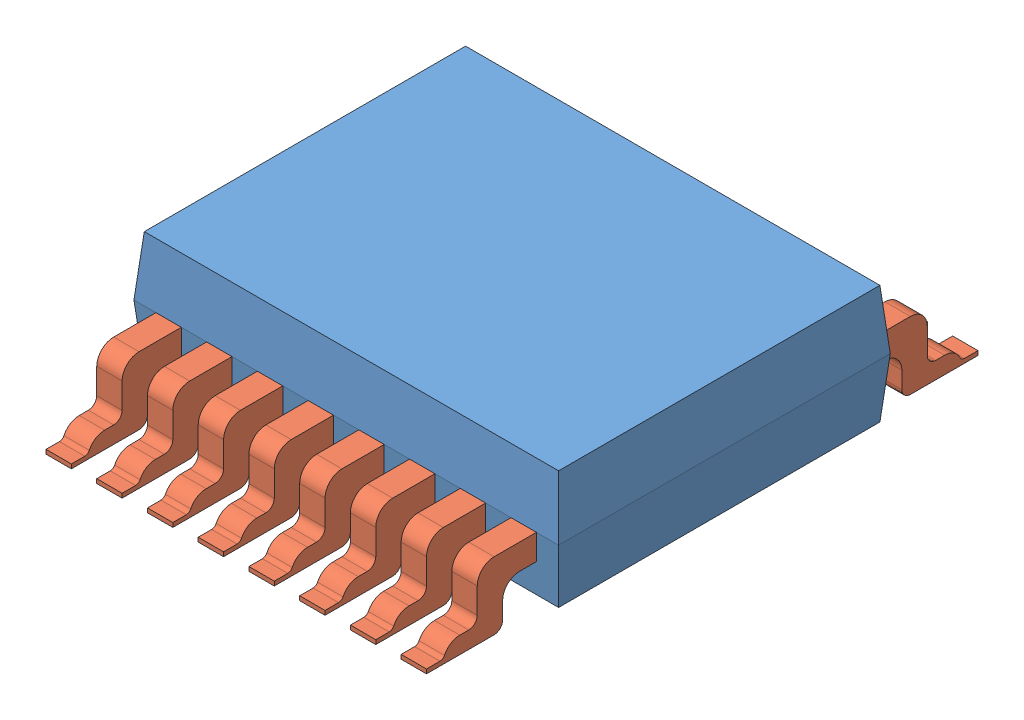
SolidWorks assembly P9813-SSOP16, configuration Défaut. Lengths in mm.
Overall size (5.02 1.5 6.52).
17 component instances, 2 part files, 2 mates.
Components (placement in the parent):
- P9813 Box-1: P9813 Box [Défaut] at (-2.298 -0.5448 6.9225) size (5.02 1.4 3.92)
- P9813 Foot-1: P9813 Foot [Défaut] at (2.1008 -0.6448 2.6612) size (0.3 0.8 1.3)
- P9813 Foot-17: P9813 Foot [Défaut] at (1.5008 -0.6448 2.6612) size (0.3 0.8 1.3)
- P9813 Foot-18: P9813 Foot [Défaut] at (0.9008 -0.6448 2.6612) size (0.3 0.8 1.3)
- P9813 Foot-19: P9813 Foot [Défaut] at (0.3008 -0.6448 2.6612) size (0.3 0.8 1.3)
- P9813 Foot-20: P9813 Foot [Défaut] at (-0.2992 -0.6448 2.6612) size (0.3 0.8 1.3)
- P9813 Foot-21: P9813 Foot [Défaut] at (-0.8992 -0.6448 2.6612) size (0.3 0.8 1.3)
- P9813 Foot-22: P9813 Foot [Défaut] at (-1.4992 -0.6448 2.6612) size (0.3 0.8 1.3)
- P9813 Foot-23: P9813 Foot [Défaut] at (-2.0992 -0.6448 2.6612) size (0.3 0.8 1.3)
- P9813 Foot-25: P9813 Foot [Défaut] at (2.4008 -0.6448 7.3837) x (-1 0 0) z (0 0 -1) size (0.3 0.8 1.3)
- P9813 Foot-26: P9813 Foot [Défaut] at (1.8008 -0.6448 7.3837) x (-1 0 0) z (0 0 -1) size (0.3 0.8 1.3)
- P9813 Foot-27: P9813 Foot [Défaut] at (1.2008 -0.6448 7.3837) x (-1 0 0) z (0 0 -1) size (0.3 0.8 1.3)
- P9813 Foot-28: P9813 Foot [Défaut] at (0.6008 -0.6448 7.3837) x (-1 0 0) z (0 0 -1) size (0.3 0.8 1.3)
- P9813 Foot-29: P9813 Foot [Défaut] at (0.0008 -0.6448 7.3837) x (-1 0 0) z (0 0 -1) size (0.3 0.8 1.3)
- P9813 Foot-30: P9813 Foot [Défaut] at (-0.5992 -0.6448 7.3837) x (-1 0 0) z (0 0 -1) size (0.3 0.8 1.3)
- P9813 Foot-31: P9813 Foot [Défaut] at (-1.1992 -0.6448 7.3837) x (-1 0 0) z (0 0 -1) size (0.3 0.8 1.3)
- P9813 Foot-32: P9813 Foot [Défaut] at (-1.7992 -0.6448 7.3837) x (-1 0 0) z (0 0 -1) size (0.3 0.8 1.3)
Mates (geometry in assembly coordinates):
- Parallèle10: parallel aligned: plane of box-1 through (-2.298 -0.5448 6.9225) normal (0 -1 0); plane of foot-1 through (2.1008 -0.6448 2.6612) normal (0 -1 0)
- Coïncidente14: coincident aligned: line of box-1 through (2.6633 0.1552 3.0612) axis (-1 0 0); line of foot-1 through (2.4008 0.1552 3.0612) axis (-1 0 0)
